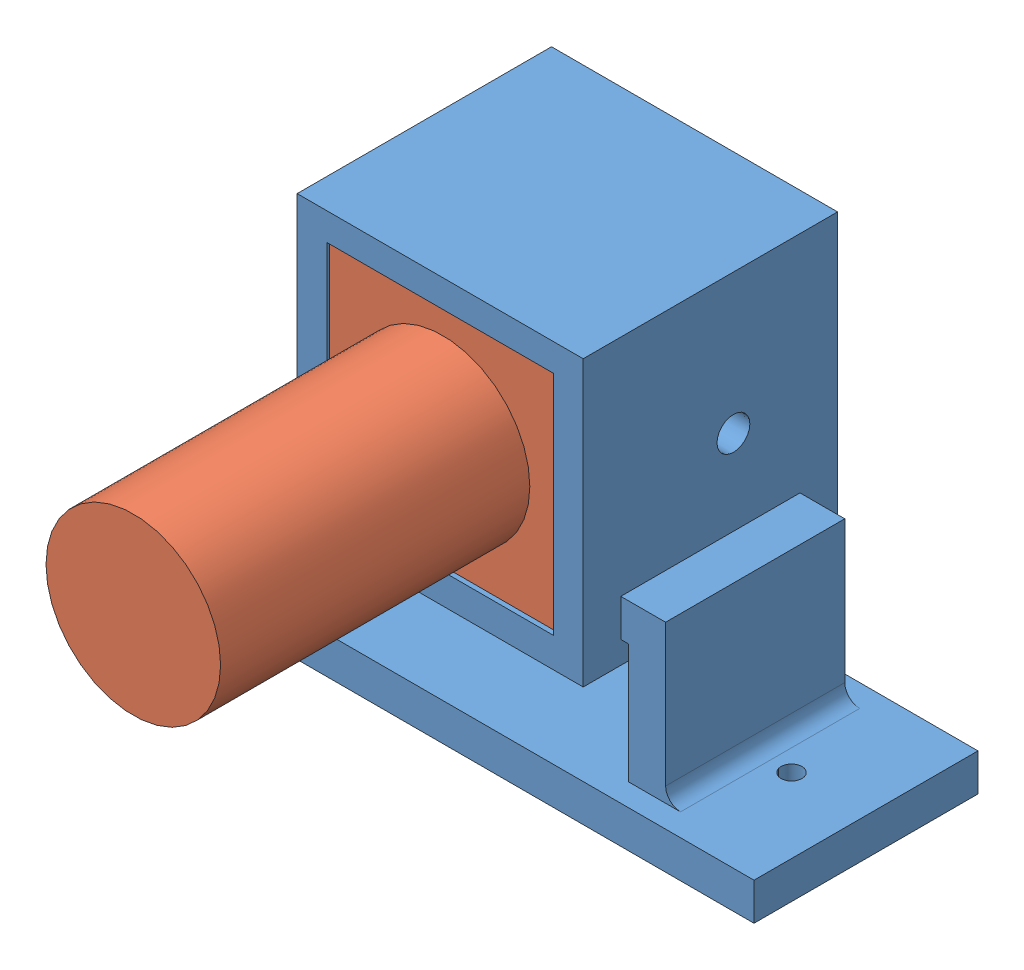
SolidWorks assembly camer_case, configuration Default. Lengths in mm.
Overall size (101.6 109.32 95.46).
2 component instances, 2 part files, 6 mates.
Components (placement in the parent):
- cam_case-1: cam_case [Default] at origin size (101.6 109.32 43.27)
- camera-1: camera [Default] at (19.2436 19.508 10.16) size (38.5 38.2 90.38)
Mates (geometry in assembly coordinates):
- Coincident1: coincident aligned: plane of cam_case-1 through (0 0 0) normal (0 0 1)
- Coincident2: coincident aligned: plane of cam_case-1 through (0 0 0) normal (0 1 0)
- Coincident3: coincident aligned: plane of cam_case-1 through (0 0 0) normal (1 0 0)
- Coincident4: coincident anti-aligned: plane of cam_case-1 through (0 0 10.16) normal (0 0 1); plane of camera-1 through (19.2436 19.508 10.16) normal (0 0 -1)
- Coincident5: coincident anti-aligned: plane of cam_case-1 through (-0.0064 38.608 10.16) normal (1 0 0); plane of camera-1 through (-0.0064 0.408 42.86) normal (-1 0 0)
- Coincident6: coincident anti-aligned: plane of cam_case-1 through (-0.0064 38.608 10.16) normal (0 -1 0); plane of camera-1 through (-0.0064 38.608 42.86) normal (0 1 0)
